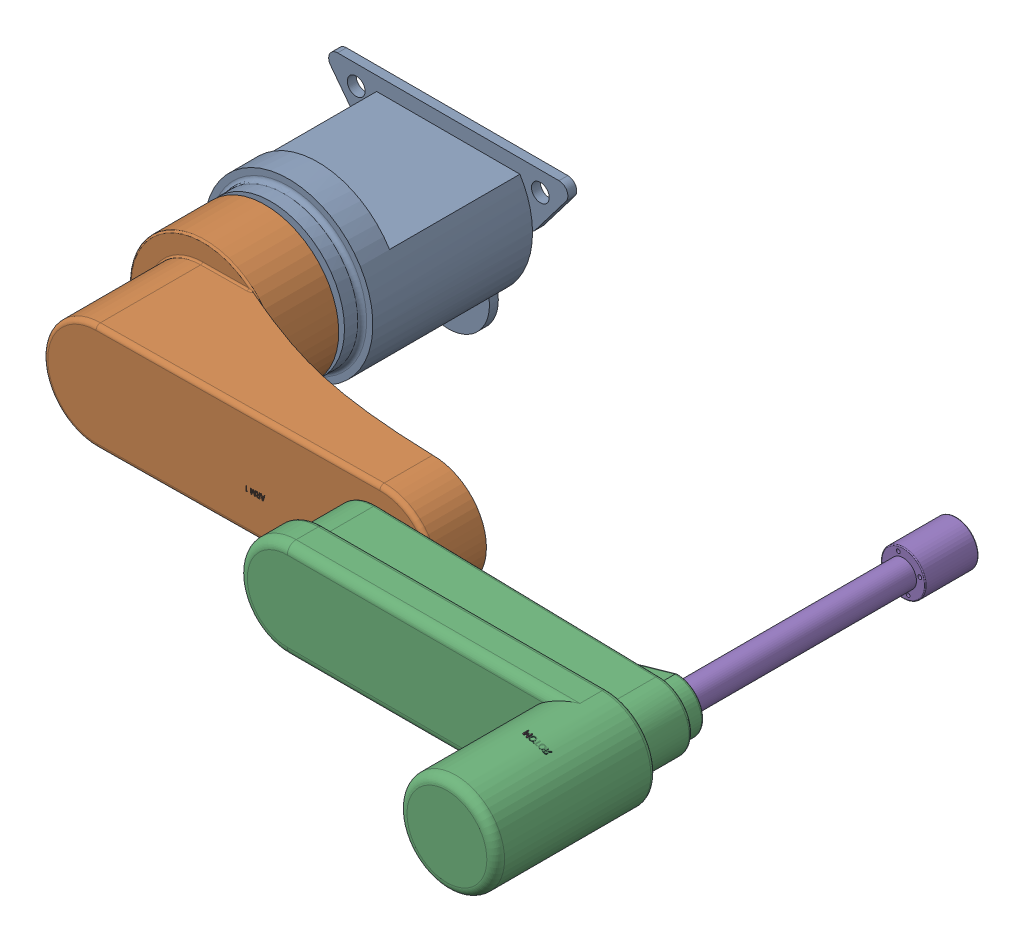
SolidWorks assembly scara, configuration Default. Lengths in mm.
Overall size (829.82 236.41 788.19).
4 component instances, 4 part files, 5 mates.
Components (placement in the parent):
- base-1: base [Default] at (-15.6854 71.833 136.6876) size (269.65 236.41 211.5)
- link1_320mm-1: link1_320mm [Default] at (-15.6854 71.833 343.1876) x (-0.999941 -0.010902 0) z (0 0 1) size (463 166 197)
- link2_320mm-2: link2_320mm [Default] at (464.2956 75.374 538.1876) x (-1 -0.000327 0) z (0 0 1) size (430 112.43 260)
- shaft-1: shaft [Default] at (624.2956 75.4264 613.8063) x (0.284594 -0.958648 0) z (0 0 1) size (50 50 410)
Mates (geometry in assembly coordinates):
- Concentric1: concentric anti-aligned: circle of base-1; cylinder of link1_320mm-1 through (-15.6854 71.833 343.1876) axis (0 0 -1) radius 45
- Coincident3: coincident anti-aligned: plane of link1_320mm-1 through (304.2956 75.3217 535.1876) normal (0 0 1); plane of link2_320mm-2 through (304.2956 75.3217 535.1876) normal (0 0 -1)
- Concentric2: concentric anti-aligned: cylinder of link1_320mm-1 through (304.2956 75.3217 533.1876) axis (0 0 1) radius 30; cylinder of link2_320mm-2 through (304.2956 75.3217 538.1876) axis (0 0 -1) radius 30
- Concentric3: concentric aligned: circle of link2_320mm-2; circle of shaft-1
- Coincident5: coincident anti-aligned: circle of base-1; circle of link1_320mm-1
